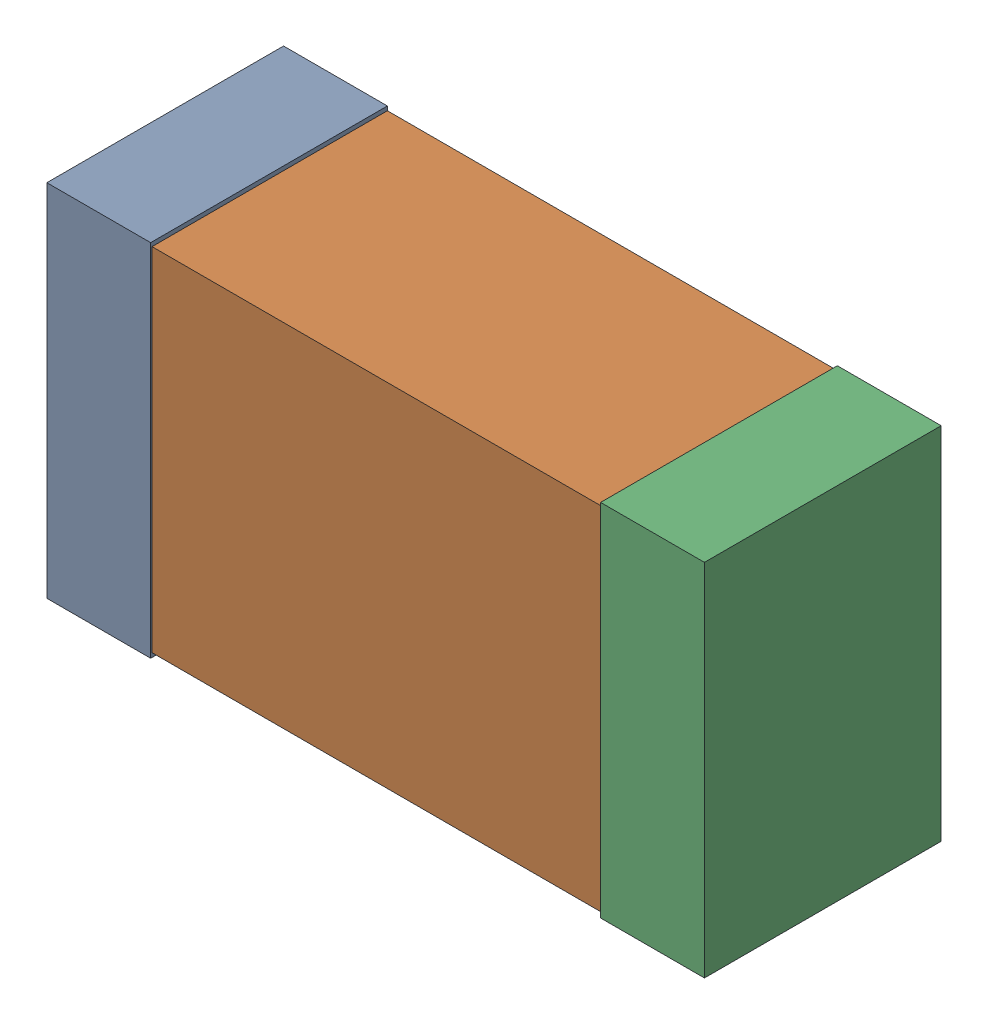
SolidWorks assembly C13_Motor_9Kanaloa_v2.0.0_Motor, configuration Default. Lengths in mm.
Overall size (2.38 1.3 0.85).
6 component instances, 2 part files, 0 mates.
Components (placement in the parent):
- 352877648-1: 352877648 [Default] at (59.647 170.434 0) size (0.38 1.3 0.85)
  - Extruded_14-1: Extruded_14 [Default] at origin size (0.38 1.3 0.85)
- 352877392-1: 352877392 [Default] at (60.647 170.434 0) size (2.2 1.27 0.85)
  - Extruded_15-1: Extruded_15 [Default] at origin size (2.2 1.27 0.85)
- 352877648-2: 352877648 [Default] at (61.647 170.434 0) size (0.38 1.3 0.85)
  - Extruded_14-1: Extruded_14 [Default] at origin size (0.38 1.3 0.85)
